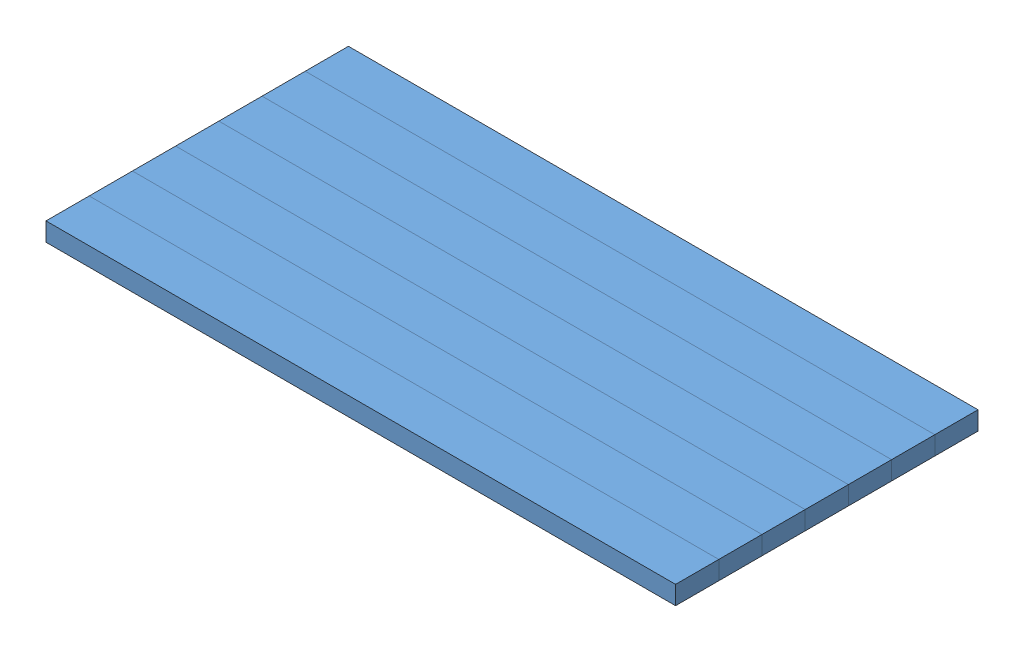
SolidWorks assembly long_side, configuration Default. Lengths in mm.
Overall size (1295.4 38.1 622.3).
7 component instances, 1 part files, 18 mates.
Components (placement in the parent):
- 51in_2x4-1: 51in_2x4 [Default] at (-580.1032 -18.8057 235.4979) x (0 0 -1) z (1 0 0) size (88.9 38.1 1295.4)
- 51in_2x4-2: 51in_2x4 [Default] at (-580.1032 -18.8057 146.5979) x (0 0 -1) z (1 0 0) size (88.9 38.1 1295.4)
- 51in_2x4-3: 51in_2x4 [Default] at (715.2968 -18.8057 -297.9021) x (0 0 1) z (-1 0 0) size (88.9 38.1 1295.4)
- 51in_2x4-4: 51in_2x4 [Default] at (715.2968 -18.8057 57.6979) x (0 0 1) z (-1 0 0) size (88.9 38.1 1295.4)
- 51in_2x4-5: 51in_2x4 [Default] at (715.2968 -18.8057 -31.2021) x (0 0 1) z (-1 0 0) size (88.9 38.1 1295.4)
- 51in_2x4-6: 51in_2x4 [Default] at (715.2968 -18.8057 -120.1021) x (0 0 1) z (-1 0 0) size (88.9 38.1 1295.4)
- 51in_2x4-7: 51in_2x4 [Default] at (715.2968 -18.8057 -209.0021) x (0 0 1) z (-1 0 0) size (88.9 38.1 1295.4)
Mates (geometry in assembly coordinates):
- Coincident2: coincident anti-aligned: plane of 51in_2x4-1 through (715.2968 0.2443 191.0479) normal (0 0 -1); plane of 51in_2x4-2 through (715.2968 0.2443 191.0479) normal (0 0 1)
- Coincident3: coincident aligned: plane of 51in_2x4-1 through (715.2968 -37.8557 279.9479) normal (0 -1 0); plane of 51in_2x4-2 through (715.2968 -37.8557 191.0479) normal (0 -1 0)
- Coincident4: coincident aligned: plane of 51in_2x4-1 through (-580.1032 -37.8557 191.0479) normal (-1 0 0); plane of 51in_2x4-2 through (-580.1032 -37.8557 102.1479) normal (-1 0 0)
- Coincident5: coincident anti-aligned: plane of 51in_2x4-2 through (715.2968 0.2443 102.1479) normal (0 0 -1); plane of 51in_2x4-4 through (-580.1032 0.2443 102.1479) normal (0 0 1)
- Coincident6: coincident anti-aligned: plane of 51in_2x4-4 through (-580.1032 0.2443 13.2479) normal (0 0 -1); plane of 51in_2x4-5 through (-580.1032 0.2443 13.2479) normal (0 0 1)
- Coincident7: coincident anti-aligned: plane of 51in_2x4-5 through (-580.1032 0.2443 -75.6521) normal (0 0 -1); plane of 51in_2x4-6 through (-580.1032 0.2443 -75.6521) normal (0 0 1)
- Coincident8: coincident anti-aligned: plane of 51in_2x4-6 through (-580.1032 0.2443 -164.5521) normal (0 0 -1); plane of 51in_2x4-7 through (-580.1032 0.2443 -164.5521) normal (0 0 1)
- Coincident9: coincident anti-aligned: plane of 51in_2x4-3 through (-580.1032 0.2443 -253.4521) normal (0 0 1); plane of 51in_2x4-7 through (-580.1032 0.2443 -253.4521) normal (0 0 -1)
- Coincident11: coincident aligned: plane of 51in_2x4-2 through (715.2968 -37.8557 191.0479) normal (0 -1 0); plane of 51in_2x4-4 through (-580.1032 -37.8557 13.2479) normal (0 -1 0)
- Coincident12: coincident aligned: plane of 51in_2x4-4 through (-580.1032 -37.8557 13.2479) normal (0 -1 0); plane of 51in_2x4-5 through (-580.1032 -37.8557 -75.6521) normal (0 -1 0)
- Coincident13: coincident aligned: plane of 51in_2x4-5 through (-580.1032 -37.8557 -75.6521) normal (0 -1 0); plane of 51in_2x4-6 through (-580.1032 -37.8557 -164.5521) normal (0 -1 0)
- Coincident14: coincident aligned: plane of 51in_2x4-6 through (-580.1032 -37.8557 -164.5521) normal (0 -1 0); plane of 51in_2x4-7 through (-580.1032 -37.8557 -253.4521) normal (0 -1 0)
- Coincident15: coincident aligned: plane of 51in_2x4-3 through (-580.1032 -37.8557 -342.3521) normal (0 -1 0); plane of 51in_2x4-7 through (-580.1032 -37.8557 -253.4521) normal (0 -1 0)
- Coincident18: coincident aligned: plane of 51in_2x4-3 through (-580.1032 -37.8557 -253.4521) normal (-1 0 0); plane of 51in_2x4-7 through (-580.1032 -37.8557 -164.5521) normal (-1 0 0)
- Coincident19: coincident aligned: plane of 51in_2x4-6 through (-580.1032 -37.8557 -75.6521) normal (-1 0 0); plane of 51in_2x4-7 through (-580.1032 -37.8557 -164.5521) normal (-1 0 0)
- Coincident20: coincident aligned: plane of 51in_2x4-5 through (-580.1032 -37.8557 13.2479) normal (-1 0 0); plane of 51in_2x4-6 through (-580.1032 -37.8557 -75.6521) normal (-1 0 0)
- Coincident21: coincident aligned: plane of 51in_2x4-4 through (-580.1032 -37.8557 102.1479) normal (-1 0 0); plane of 51in_2x4-5 through (-580.1032 -37.8557 13.2479) normal (-1 0 0)
- Coincident22: coincident aligned: plane of 51in_2x4-2 through (-580.1032 -37.8557 102.1479) normal (-1 0 0); plane of 51in_2x4-4 through (-580.1032 -37.8557 102.1479) normal (-1 0 0)
